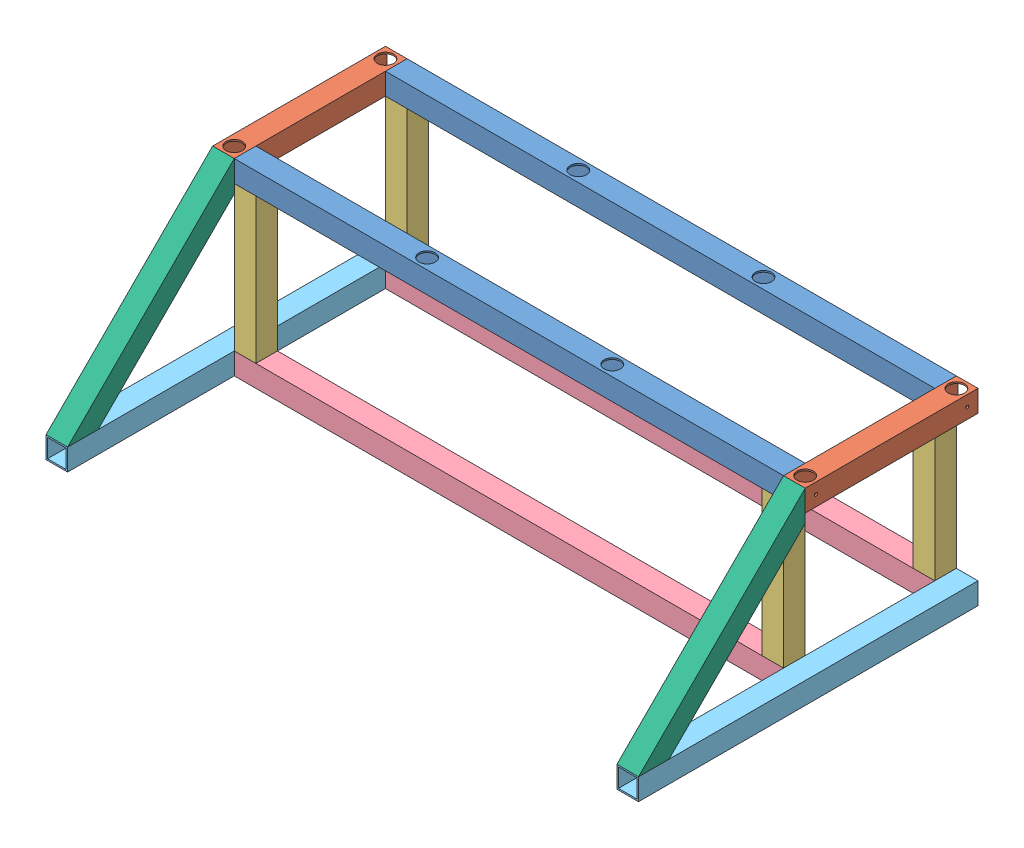
SolidWorks assembly GE-18032, configuration Default. Lengths in mm.
Overall size (1219.2 387.35 698.5).
14 component instances, 6 part files, 40 mates.
Components (placement in the parent):
- GE-18032-01-1: GE-18032-01 [Default] at (609.6 342.9 22.225) x (-1 0 0) z (0 1 0) size (1130.3 44.45 44.45)
- GE-18032-02-1: GE-18032-02 [Default] at (609.6 342.9 22.225) x (-1 0 0) z (0 1 0) size (44.45 355.6 44.45)
- GE-18032-03-1: GE-18032-03 [Default] at (609.6 342.9 22.225) x (-1 0 0) z (0 1 0) size (44.45 44.45 298.45)
- GE-18032-05-1: GE-18032-05 [Default] at (609.6 342.9 22.225) x (-1 0 0) z (0 1 0) size (1130.3 44.45 44.45)
- GE-18032-04-1: GE-18032-04 [Default] at (609.6 342.9 22.225) x (-1 0 0) z (0 1 0) size (44.45 698.5 44.45)
- GE-18032-06-1: GE-18032-06 [Default] at (609.6 342.9 22.225) x (-1 0 0) z (0 1 0) size (44.45 342.9 342.9)
- GE-18032-01-2: GE-18032-01 [Default] at (609.6 342.9 333.375) x (-1 0 0) z (0 1 0) size (1130.3 44.45 44.45)
- GE-18032-02-2: GE-18032-02 [Default] at (-565.15 342.9 22.225) x (-1 0 0) z (0 1 0) size (44.45 355.6 44.45)
- GE-18032-05-2: GE-18032-05 [Default] at (609.6 342.9 333.375) x (-1 0 0) z (0 1 0) size (1130.3 44.45 44.45)
- GE-18032-03-2: GE-18032-03 [Default] at (609.6 342.9 -288.925) x (-1 0 0) z (0 1 0) size (44.45 44.45 298.45)
- GE-18032-03-3: GE-18032-03 [Default] at (-476.25 342.9 22.225) x (-1 0 0) z (0 1 0) size (44.45 44.45 298.45)
- GE-18032-03-4: GE-18032-03 [Default] at (-476.25 342.9 -288.925) x (-1 0 0) z (0 1 0) size (44.45 44.45 298.45)
- GE-18032-04-2: GE-18032-04 [Default] at (-565.15 342.9 22.225) x (-1 0 0) z (0 1 0) size (44.45 698.5 44.45)
- GE-18032-06-2: GE-18032-06 [Default] at (-565.15 342.9 22.225) x (-1 0 0) z (0 1 0) size (44.45 342.9 342.9)
Mates (geometry in assembly coordinates):
- Coincident1: coincident anti-aligned: plane of GE-18032-03-1 through (631.825 342.9 177.8) normal (0 1 0); plane of GE-18032-01-2 through (609.6 342.9 333.375) normal (0 -1 0)
- Coincident3: coincident anti-aligned: plane of GE-18032-02-1 through (1174.75 365.125 177.8) normal (-1 0 0); plane of GE-18032-01-2 through (1174.75 387.35 333.375) normal (1 0 0)
- Coincident4: coincident: moEndPointRef_w of GE-18032-02-1; moEndPointRef_w of GE-18032-01-2
- Coincident5: coincident: moEndPointRef_w of GE-18032-01-1; moEndPointRef_w of GE-18032-02-1
- Coincident8: coincident: moEndPointRef_w of GE-18032-03-1; line of GE-18032-01-2 through (44.45 342.9 355.6) axis (1 0 0)
- Coincident9: coincident: moEndPointRef_w of GE-18032-03-1; moEndPointRef_w of GE-18032-01-2
- Coincident11: coincident: moEndPointRef_w of GE-18032-04-1; moEndPointRef_w of GE-18032-06-1
- Coincident12: coincident: moEndPointRef_w of GE-18032-01-1; moEndPointRef_w of GE-18032-02-2
- Coincident13: coincident aligned: plane of GE-18032-01-1 through (609.6 387.35 22.225) normal (0 1 0); plane of GE-18032-02-2 through (44.45 387.35 64.6723) normal (0 1 0)
- Coincident14: coincident aligned: plane of GE-18032-03-1 through (1145.8543 44.45 311.15) normal (0 0 -1); plane of GE-18032-05-2 through (609.6 44.45 311.15) normal (0 0 -1)
- Coincident15: coincident: moEndPointRef_w of GE-18032-06-1; line of GE-18032-01-2 through (1174.75 387.35 355.6) axis (-1 0 0)
- Coincident16: coincident anti-aligned: plane of GE-18032-04-1 through (1174.75 22.225 177.8) normal (-1 0 0); plane of GE-18032-05-2 through (1174.75 44.45 333.375) normal (1 0 0)
- Coincident18: coincident: moEndPointRef_w of GE-18032-05-1; moEndPointRef_w of GE-18032-04-1
- Coincident20: coincident anti-aligned: plane of GE-18032-06-1 through (1174.75 368.3 355.6) normal (0 0 -1); plane of GE-18032-01-2 through (609.6 387.35 355.6) normal (0 0 1)
- Coincident26: coincident aligned: plane of GE-18032-02-1 through (1219.2 365.125 177.8) normal (1 0 0); plane of GE-18032-06-1 through (1219.2 215.9 349.25) normal (1 0 0)
- Coincident28: coincident aligned: plane of GE-18032-03-1 through (1145.8543 44.45 355.6) normal (0 0 1); plane of GE-18032-05-2 through (609.6 44.45 355.6) normal (0 0 1)
- Coincident29: coincident anti-aligned: plane of GE-18032-03-1 through (631.825 44.45 177.8) normal (0 -1 0); plane of GE-18032-05-2 through (609.6 44.45 333.375) normal (0 1 0)
- Coincident30: coincident aligned: plane of GE-18032-03-1 through (1130.3 44.45 337.6466) normal (-1 0 0); plane of GE-18032-03-2 through (1130.3 44.45 26.4966) normal (-1 0 0)
- Coincident31: coincident aligned: plane of GE-18032-05-1 through (609.6 44.45 0) normal (0 0 -1); plane of GE-18032-03-2 through (1145.8543 44.45 0) normal (0 0 -1)
- Coincident32: coincident anti-aligned: plane of GE-18032-01-1 through (609.6 342.9 22.225) normal (0 -1 0); plane of GE-18032-03-2 through (631.825 342.9 -133.35) normal (0 1 0)
- Coincident33: coincident anti-aligned: plane of GE-18032-05-1 through (609.6 44.45 22.225) normal (0 1 0); plane of GE-18032-03-2 through (631.825 44.45 -133.35) normal (0 -1 0)
- Coincident34: coincident aligned: plane of GE-18032-05-1 through (609.6 44.45 0) normal (0 0 -1); plane of GE-18032-04-2 through (44.45 44.45 0) normal (0 0 -1)
- Coincident35: coincident anti-aligned: plane of GE-18032-05-1 through (44.45 44.45 22.225) normal (-1 0 0); plane of GE-18032-04-2 through (44.45 22.225 177.8) normal (1 0 0)
- Coincident36: coincident aligned: plane of GE-18032-05-1 through (609.6 44.45 22.225) normal (0 1 0); plane of GE-18032-04-2 through (44.45 44.45 64.6723) normal (0 1 0)
- Coincident37: coincident anti-aligned: line of GE-18032-03-4 through (44.45 44.45 44.45) axis (0 0 -1); line of GE-18032-04-2 through (44.45 44.45 0) axis (0 0 1)
- Coincident38: coincident anti-aligned: plane of GE-18032-05-1 through (609.6 44.45 22.225) normal (0 1 0); plane of GE-18032-03-4 through (-454.025 44.45 -133.35) normal (0 -1 0)
- Coincident39: coincident aligned: plane of GE-18032-05-1 through (609.6 44.45 0) normal (0 0 -1); plane of GE-18032-03-4 through (60.0043 44.45 0) normal (0 0 -1)
- Coincident40: coincident aligned: plane of GE-18032-01-2 through (609.6 342.9 333.375) normal (0 -1 0); plane of GE-18032-02-2 through (44.45 342.9 67.8473) normal (0 -1 0)
- Coincident41: coincident: line of GE-18032-05-2 through (44.45 44.45 355.6) axis (0 0 -1); plane of GE-18032-03-3 through (44.45 44.45 337.6466) normal (-1 0 0)
- Coincident42: coincident anti-aligned: plane of GE-18032-05-2 through (609.6 44.45 333.375) normal (0 1 0); plane of GE-18032-03-3 through (-454.025 44.45 177.8) normal (0 -1 0)
- Coincident43: coincident aligned: plane of GE-18032-05-2 through (609.6 44.45 355.6) normal (0 0 1); plane of GE-18032-03-3 through (60.0043 44.45 355.6) normal (0 0 1)
- Coincident44: coincident anti-aligned: plane of GE-18032-04-2 through (44.45 44.45 64.6723) normal (0 1 0); plane of GE-18032-06-2 through (0 44.45 667.0691) normal (0 -1 0)
- Coincident45: coincident aligned: plane of GE-18032-04-2 through (0 22.225 177.8) normal (-1 0 0); plane of GE-18032-06-2 through (0 215.9 349.25) normal (-1 0 0)
- Coincident46: coincident anti-aligned: line of GE-18032-04-2 through (0 44.45 698.5) axis (1 0 0); line of GE-18032-06-2 through (44.45 44.45 698.5) axis (-1 0 0)
- Coincident47: coincident anti-aligned: line of GE-18032-02-2 through (44.45 387.35 355.6) axis (-1 0 0); line of GE-18032-06-2 through (0 387.35 355.6) axis (1 0 0)
- Coincident48: coincident anti-aligned: plane of ? through (609.6 0 22.225) normal (0 -1 0)
- Coincident49: coincident anti-aligned: plane of ? through (0 365.125 177.8) normal (-1 0 0)
- Coincident50: coincident anti-aligned: plane of ? through (44.45 0 67.8473) normal (0 -1 0)
- Coincident51: coincident anti-aligned: plane of ? through (609.6 44.45 0) normal (0 0 -1)
- Coincident52: coincident anti-aligned: plane of ? through (0 365.125 177.8) normal (-1 0 0)
